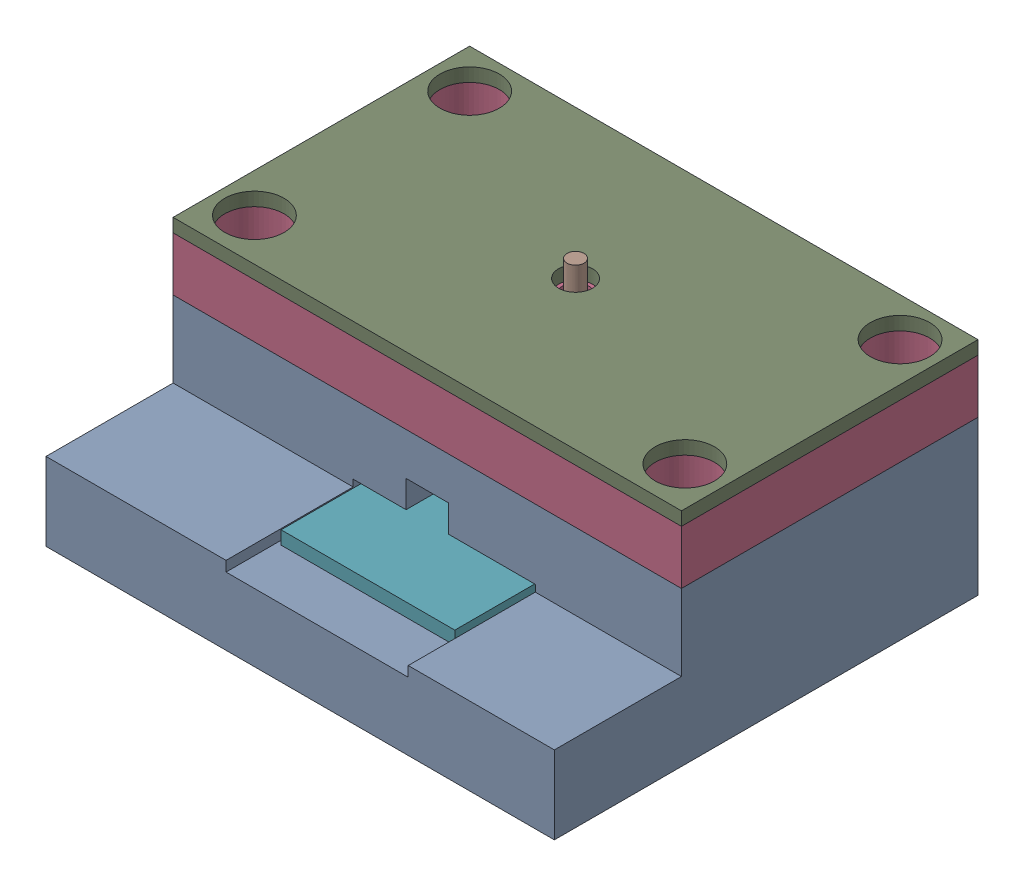
SolidWorks assembly PrototypeAssembly, configuration Default. Lengths in mm.
Overall size (60 28.2 50).
9 component instances, 9 part files, 20 mates.
Components (placement in the parent):
- BottomHousing-1: BottomHousing [Default] at (-44.725 -0.3064 26.796) size (60 18.2 50)
- Coil_SP43-221K-1: Coil_SP43-221K [Default] at (-14.725 10.0136 -5.704) size (3.9 1.7 3.9)
- Core_SP43-221K-1: Core_SP43-221K [Default] at (-14.725 9.2636 -5.704) size (4.5 3.2 4)
- DelrinGuide-1: DelrinGuide [Default] at (-44.725 17.8936 11.796) size (60 6.35 35)
- Elastomer-1: Elastomer [Default] at (-7.475 12.8936 9.296) x (0 0 -1) z (1 0 0) size (30 5 14.5)
- Magnet_4mm-1: Magnet_4mm [Default] at (-14.725 17.8936 -5.704) x (-0.740663 0 0.671877) z (-0.671877 0 -0.740663) size (3 4 3)
- PCB_LargeInductor-1: PCB_LargeInductor [Default] at (-2.475 7.6936 -9.204) x (-1 0 0) z (0 0 -1) size (20.5 1.57 30)
- Tactor-1: Tactor [Default] at (-14.725 21.8936 -5.704) size (2 6 2)
- TouchSurface-1: TouchSurface [Default] at (-44.725 24.2436 11.796) size (60 1.59 35)
Mates (geometry in assembly coordinates):
- Coincident1: coincident anti-aligned: plane of Core_SP43-221K-1 through (-14.725 9.2636 -5.704) normal (0 -1 0); plane of PCB_LargeInductor-1 through (-2.475 9.2636 -9.204) normal (0 1 0)
- Concentric1: concentric aligned: circle of Core_SP43-221K-1; circle of PCB_LargeInductor-1
- Concentric2: concentric aligned: circle of Coil_SP43-221K-1; circle of PCB_LargeInductor-1
- Coincident2: coincident anti-aligned: plane of Coil_SP43-221K-1 through (-14.725 10.0136 -5.704) normal (0 -1 0); plane of Core_SP43-221K-1 through (-14.725 10.0136 -5.704) normal (0 1 0)
- Concentric3: concentric aligned: circle of BottomHousing-1; circle of PCB_LargeInductor-1
- Coincident6: coincident anti-aligned: plane of BottomHousing-1 through (-44.725 7.6936 26.796) normal (0 1 0); plane of PCB_LargeInductor-1 through (-2.475 7.6936 -9.204) normal (0 -1 0)
- Parallel2: parallel aligned: plane of BottomHousing-1 through (-44.725 9.6936 26.796) normal (0 0 1); plane of PCB_LargeInductor-1 through (-2.475 9.2636 20.796) normal (0 0 1)
- Coincident8: coincident anti-aligned: plane of BottomHousing-1 through (-44.725 12.8936 26.796) normal (0 1 0); plane of Elastomer-1 through (-7.475 12.8936 9.296) normal (0 -1 0)
- Coincident9: coincident anti-aligned: plane of BottomHousing-1 through (-21.975 17.8936 -20.704) normal (0 0 1); plane of Elastomer-1 through (-7.475 17.8936 -20.704) normal (0 0 -1)
- Coincident10: coincident anti-aligned: plane of BottomHousing-1 through (-7.475 17.8936 -20.704) normal (-1 0 0); plane of Elastomer-1 through (-7.475 17.8936 9.296) normal (1 0 0)
- Coincident11: coincident anti-aligned: plane of BottomHousing-1 through (-44.725 17.8936 26.796) normal (0 1 0); plane of DelrinGuide-1 through (-44.725 17.8936 11.796) normal (0 -1 0)
- Concentric4: concentric aligned: circle of DelrinGuide-1; circle of PCB_LargeInductor-1
- Coincident12: coincident aligned: plane of BottomHousing-1 through (-44.725 9.6936 26.796) normal (-1 0 0); plane of DelrinGuide-1 through (-44.725 24.2436 11.796) normal (-1 0 0)
- Concentric5: concentric aligned: circle of DelrinGuide-1; circle of Magnet_4mm-1
- Coincident13: coincident anti-aligned: plane of Elastomer-1 through (-7.475 17.8936 9.296) normal (0 1 0); plane of Magnet_4mm-1 through (-14.725 17.8936 -5.704) normal (0 -1 0)
- Coincident14: coincident anti-aligned: plane of Magnet_4mm-1 through (-14.725 21.8936 -5.704) normal (0 1 0); plane of Tactor-1 through (-14.725 21.8936 -5.704) normal (0 -1 0)
- Concentric6: concentric aligned: circle of DelrinGuide-1; circle of Tactor-1
- Coincident15: coincident aligned: line of DelrinGuide-1 through (-44.725 24.2436 11.796) axis (1 0 0); line of TouchSurface-1 through (-44.725 24.2436 11.796) axis (1 0 0)
- Coincident16: coincident anti-aligned: plane of DelrinGuide-1 through (-44.725 24.2436 11.796) normal (0 1 0); plane of TouchSurface-1 through (-44.725 24.2436 11.796) normal (0 -1 0)
- Concentric7: concentric aligned: circle of Tactor-1; circle of TouchSurface-1
